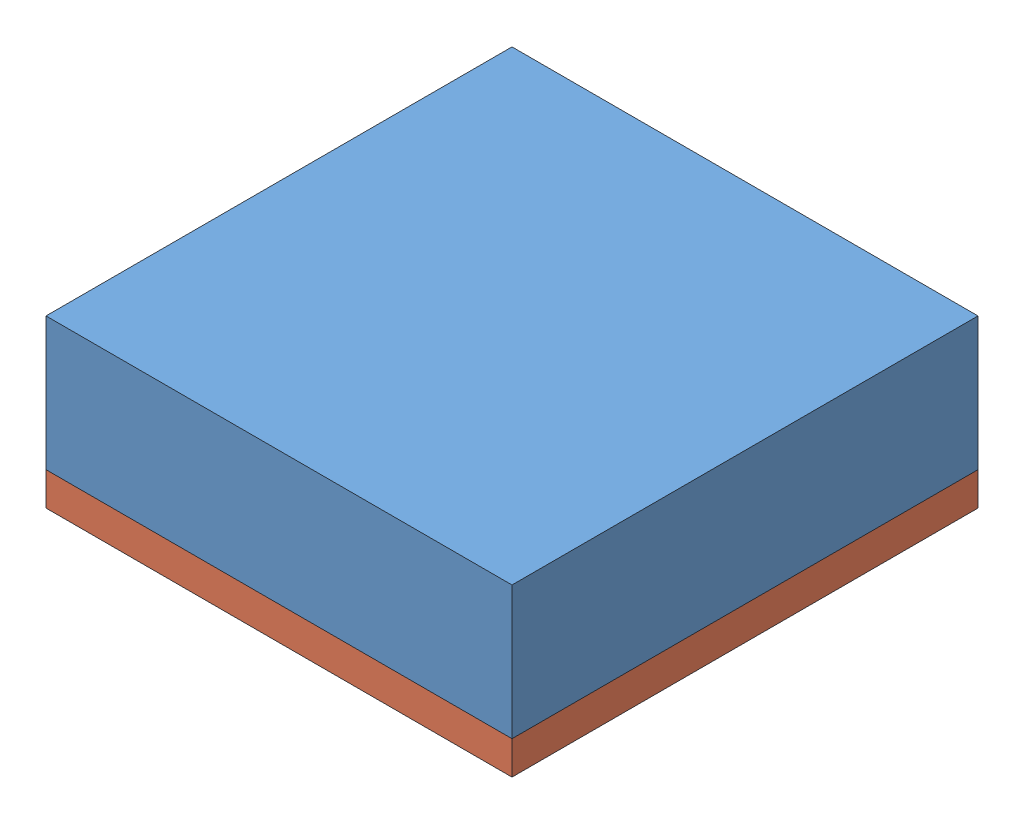
SolidWorks assembly OpAmp, configuration Default. Lengths in mm.
Overall size (70 28.12 70).
4 component instances, 3 part files, 7 mates.
Components (placement in the parent):
- Part2-1: Part2 [Default] at (-1.7924 21.1422 78.7206) size (70 20 70)
- Part1-1: Part1 [Default] at (-1.7924 16.1422 78.7206) size (70 5 70)
- 91290A138_BLACK-OXIDE CLASS 12.9 SOCKET HEAD CAP SCREW-1: 91290A138_BLACK-OXIDE CLASS 12.9 SOCKET HEAD CAP SCREW [91290A138] at (-20.2924 13.1422 78.7206) x (-0.33762 0 -0.941282) z (0 -1 0) size (7 7 9.29)
- 91290A138_BLACK-OXIDE CLASS 12.9 SOCKET HEAD CAP SCREW-2: 91290A138_BLACK-OXIDE CLASS 12.9 SOCKET HEAD CAP SCREW [91290A138] at (16.7076 13.1422 78.7206) x (-0.33762 0 -0.941282) z (0 -1 0) size (7 7 9.29)
Mates (geometry in assembly coordinates):
- Coincident1: coincident anti-aligned: plane of Part2-1 through (-1.7924 21.1422 78.7206) normal (0 -1 0); plane of Part1-1 through (-1.7924 21.1422 78.7206) normal (0 1 0)
- Coincident2: coincident aligned: plane of Part2-1 through (-36.7924 41.1422 43.7206) normal (0 0 -1); plane of Part1-1 through (-36.7924 21.1422 43.7206) normal (0 0 -1)
- Coincident3: coincident aligned: plane of Part2-1 through (-36.7924 41.1422 43.7206) normal (-1 0 0); plane of Part1-1 through (-36.7924 21.1422 43.7206) normal (-1 0 0)
- Concentric1: concentric aligned: circle of Part1-1; circle of 91290A138_BLACK-OXIDE CLASS 12.9 SOCKET HEAD CAP SCREW-1
- Coincident4: coincident aligned: plane of Part1-1 through (-1.7924 18.1422 78.7206) normal (0 -1 0); circle of 91290A138_BLACK-OXIDE CLASS 12.9 SOCKET HEAD CAP SCREW-1
- Concentric2: concentric anti-aligned: circle of Part1-1; circle of 91290A138_BLACK-OXIDE CLASS 12.9 SOCKET HEAD CAP SCREW-2
- Coincident5: coincident aligned: plane of Part1-1 through (-1.7924 18.1422 78.7206) normal (0 -1 0); plane of 91290A138_BLACK-OXIDE CLASS 12.9 SOCKET HEAD CAP SCREW-2 through (16.7076 18.1422 78.7206) normal (0 -1 0)
